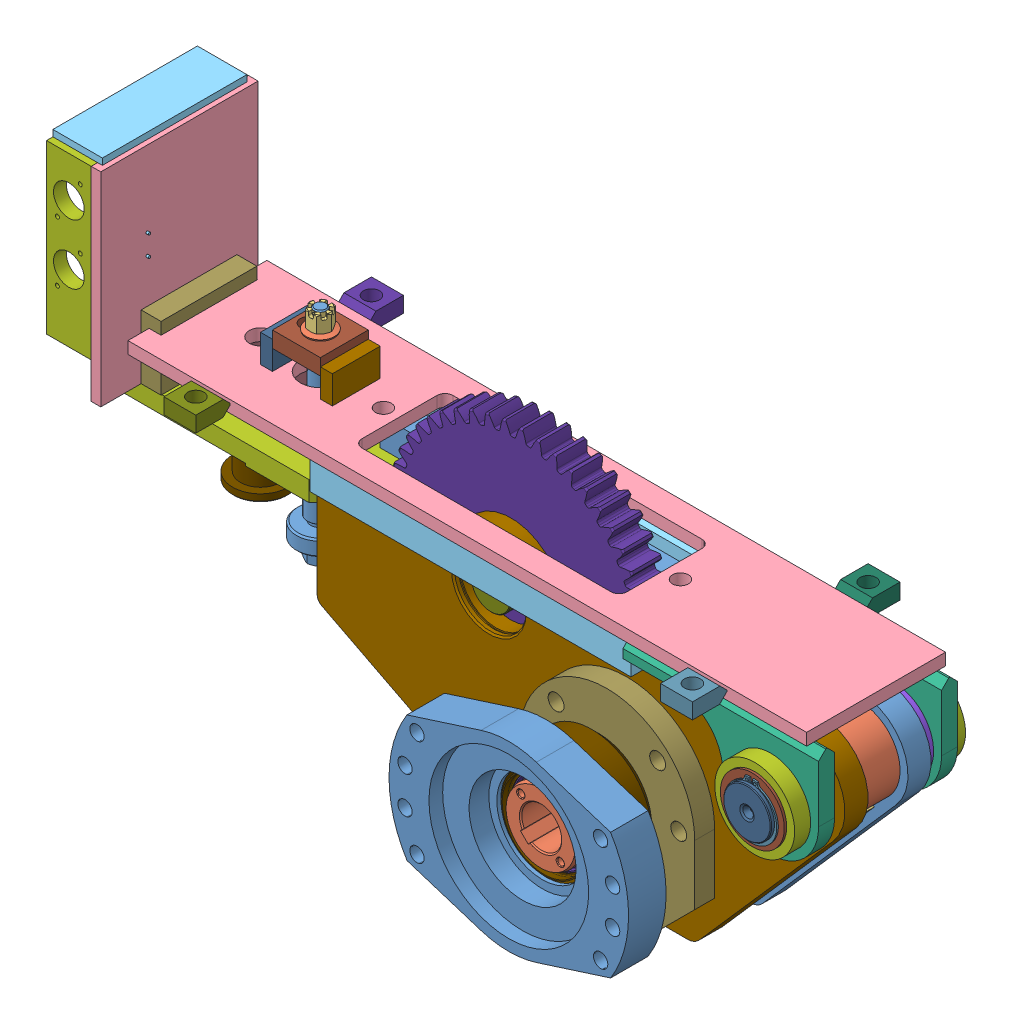
SolidWorks assembly g1_3_1_1, configuration 默认. Lengths in mm.
Overall size (943 530 331.8).
107 component instances, 72 part files, 57 mates.
Components (placement in the parent):
- g1_3_1_1_5_1-1: g1_3_1_1_5_1 [默认] at (328.5367 -95 30) x (-1 0 0) z (0 1 0) size (926 108 318.6)
  - g1_3_1_1_5-1_af1_1-1: g1_3_1_1_5-1_af1_1 [默认] at origin size (661 29 318.6)
  - g1_3_1_1_5-2_af0_1-1: g1_3_1_1_5-2_af0_1 [默认] at (-213.2 29 0) size (100 50 100)
  - g1_3_1_1_5-4_1-1: g1_3_1_1_5-4_1 [默认] at (-149.9151 54 -132.7301) x (0 1 0) z (-0.659692 0 0.751536) size (50 10 223)
  - g1_3_1_1_5-5_1-1: g1_3_1_1_5-5_1 [默认] at (20.5 54 -217) x (1 0 0) z (0 1 0) size (194 10 50)
  - g1_3_1_1_5-6_1-1: g1_3_1_1_5-6_1 [默认] at (248.4498 54 -161.5242) x (0 1 0) z (0.890083 0 0.455798) size (50 10 284)
  - g1_3_1_1_5-7_1-1: g1_3_1_1_5-7_1 [默认] at (377.8 54 -43.9) x (0 0 -1) z (0 1 0) size (87 10 50)
  - g1_3_1_1_5-9_af0_1-1: g1_3_1_1_5-9_af0_1 [默认] at (502.8 54 24.6) x (1 0 0) z (0 1 0) size (300 25 108)
  - g1_3_1_1_5-8_1-1: g1_3_1_1_5-8_1 [默认] at (437.8 54 49.6) x (1 0 0) z (0 1 0) size (60 50 60)
  - g1_3_1_1_5-1_af0_1-1: g1_3_1_1_5-1_af0_1 [默认] at (0 79 0) size (661 29 318.6)
- g1_3_1_1_4_1-1: g1_3_1_1_4_1 [默认] at (541.7367 -95 -33.3) x (1 0 0) z (0 -1 0) size (80 234 80)
  - g1_3_1_1_4-1_1-1: g1_3_1_1_4-1_1 [默认] at origin size (60 234 60.04)
  - g1_3_1_1_4-3_1-2: g1_3_1_1_4-3_1 [默认] at (0 224.3 0) size (80 3 80)
  - g1_3_1_1_4-2_1-1: g1_3_1_1_4-2_1 [默认] at (0 174.3 0) size (72 50 72)
  - g1_3_1_1_4-2_1-2: g1_3_1_1_4-2_1 [默认] at (0 9.7 0) size (72 50 72)
  - g1_3_1_1_4-2_1-3: g1_3_1_1_4-2_1 [默认] at (0 62.7 0) size (72 50 72)
  - g1_3_1_1_4-2_1-4: g1_3_1_1_4-2_1 [默认] at (0 121.3 0) size (72 50 72)
- g1_3_1_1_2_1-1: g1_3_1_1_2_1 [默认] at (328.5367 -195.4 0) x (1 0.000801 0) z (0.000801 -1 0) size (219.6 152 245)
  - g1_3_1_1_2-1_1-1: g1_3_1_1_2-1_1 [默认] at origin size (219.6 61 245)
  - g1_3_1_1_2-2_1-1: g1_3_1_1_2-2_1 [默认] at (0 152 0) x (-0.047609 0 0.998866) z (0 1 0) size (120.16 120.16 117)
  - g1_3_1_1_2-3_1-1: g1_3_1_1_2-3_1 [默认] at (-20.1525 129 20.1525) x (0 -1 0) z (0.707107 0 0.707107) size (28 11 14)
- g1_3_1_1_3_1-1: g1_3_1_1_3_1 [默认] at (155.7367 -78.4 83.75) x (0 0 -1) z (-0.004458 0.99999 0) size (103.5 321.87 322.01)
  - g1_3_1_1_3-1_1-1: g1_3_1_1_3-1_1 [默认] at origin size (103.5 52 52)
  - _X2_60F08F6E_X0_g1_3_1_1_3-2_1-1: _X2_60F08F6E_X0_g1_3_1_1_3-2_1 [默认] at (25 0 0) x (0 0 1) z (1 0 0) size (322.01 321.87 50.08)
- g1_3_1_1_1_2-1: g1_3_1_1_1_2 [默认] at (328.5367 -195.4 123.8) x (1 0.000801 0) z (0.000801 -1 0) size (300 165.8 228)
  - g1_3_1_1_1_1_1-1: g1_3_1_1_1_1_1 [默认] at origin size (300 112 228)
    - g1_3_1_1_1_1-2_af0_1-1: g1_3_1_1_1_1-2_af0_1 [默认] at (0 50 0) size (150 65 150)
    - g1_3_1_1_1_1-3_af0_1-1: g1_3_1_1_1_1-3_af0_1 [默认] at (0 140 0) size (300 47 228)
  - g1_3_1_1_1-2_1-1: g1_3_1_1_1-2_1 [默认] at (0 122.2 0) x (0.707107 0 0.707107) z (0.707107 0 -0.707107) size (90 126 90)
  - 80_gb894_1_1-1: 80_gb894_1_1 [默认] at (-2.4 11.1 -38.1746) x (1 0 0) z (0 -1 0) size (85.83 90.87 2.5)
- g1_3_1_1_6_1-1: g1_3_1_1_6_1 [默认] at (155.7367 0 84) x (-1 0 0) z (0 0 1) size (875 200 260)
  - g1_3_1_1_6-4_af0_1-1: g1_3_1_1_6-4_af0_1 [默认] at origin size (850 15 174)
  - g1_3_1_1_6-8_1-1: g1_3_1_1_6-8_1 [默认] at (0 40 57) x (1 0 0) z (0 -1 0) size (402 20 44.8)
  - g1_3_1_1_6-8_1-2: g1_3_1_1_6-8_1 [默认] at (0 40 -77) x (1 0 0) z (0 -1 0) size (402 20 44.8)
  - g1_3_1_1_6-1_1-1: g1_3_1_1_6-1_1 [默认] at (-386 95 -87) x (1 0 0) z (0 -1 0) size (245 20 140)
  - g1_3_1_1_6-1_1-2: g1_3_1_1_6-1_1 [默认] at (-386 95 67) x (1 0 0) z (0 -1 0) size (245 20 140)
  - g1_3_1_1_6-3_1-1: g1_3_1_1_6-3_1 [默认] at (-386 95 87) x (-1 0 0) z (0 1 0) size (100 20 100)
  - g1_3_1_1_6-3_1-2: g1_3_1_1_6-3_1 [默认] at (-386 95 -107) x (-1 0 0) z (0 1 0) size (100 20 100)
  - g1_3_1_1_6-2_1-1: g1_3_1_1_6-2_1 [默认] at (-386 95 57) x (-1 0 0) z (0 1 0) size (100 10 100)
  - g1_3_1_1_6-2_1-2: g1_3_1_1_6-2_1 [默认] at (-386 95 -57) x (1 0 0) z (0 1 0) size (100 10 100)
  - g1_3_1_1_6-9_1-1: g1_3_1_1_6-9_1 [默认] at (220 -17 0) x (0 1 0) z (0 0 -1) size (35 15 60)
  - g1_3_1_1_6-9_af0_1-1: g1_3_1_1_6-9_af0_1 [默认] at (310 -17 0) x (0 1 0) z (0 0 1) size (35 15 60)
  - g1_3_1_1_6-10_1-1: g1_3_1_1_6-10_1 [默认] at (265 -45 0) size (60 20 60)
  - g1_3_1_1_6-12_af0_1-1: g1_3_1_1_6-12_af0_1 [默认] at (434 25 0.5) x (0 0 1) z (0 -1 0) size (120 25 80)
  - g1_3_1_1_6-11_af0_1-1: g1_3_1_1_6-11_af0_1 [默认] at (357 15 0) size (94 40 60)
  - g1_3_1_1_6-5_af0_1-1: g1_3_1_1_6-5_af0_1 [默认] at (-311 -5 108.5) x (0 0 -1) z (1 0 0) size (43 19.6 40)
  - g1_3_1_1_6-5_af1_1-1: g1_3_1_1_6-5_af1_1 [默认] at (-311 -5 -108.5) x (0 0 1) z (-1 0 0) size (43 19.6 40)
  - g1_3_1_1_6-5_af2_1-1: g1_3_1_1_6-5_af2_1 [默认] at (311 -5 108.5) x (0 0 -1) z (1 0 0) size (43 19.6 40)
  - g1_3_1_1_6-5_af3_1-1: g1_3_1_1_6-5_af3_1 [默认] at (311 -5 -108.5) x (0 0 1) z (-1 0 0) size (43 19.6 40)
- g1_3_1_1-1_1-1: g1_3_1_1-1_1 [默认] at (-184.2633 -45.5 84) x (1 0 -0.00083) z (-0.00083 0 -1) size (70 135 70)
- g1_3_1_1_7_1-1: g1_3_1_1_7_1 [默认] at (-109.2633 -16.0167 84) x (0 1 0) z (0.020278 0 0.999794) size (272.02 60 60)
  - g1_3_1_1_7-1_1-1: g1_3_1_1_7-1_1 [默认] at origin size (272.02 60 60)
  - a35_5_gb1972_1-1: a35_5_gb1972_1 [默认] at (39.2167 0 0) x (0 0.075145 0.997173) z (0 0.997173 -0.075145) size (35.5 7.2 35.5)
  - a35_5_gb1972_1-2: a35_5_gb1972_1 [默认] at (62.8167 0 0) x (0 -0.99777 0.066751) z (0 -0.066751 -0.99777) size (35.5 7.2 35.5)
  - m16a_gb6178_1-1: m16a_gb6178_1 [默认] at (85.8167 13.8564 0) x (0 -1 0) z (-1 0 0) size (27.71 24 20.8)
- g1_3_1_1_8_1-1: g1_3_1_1_8_1 [默认] at (-273.2633 62.5 96.5) x (0 0 -1) z (0 1 0) size (197 71 268.3)
  - g1_3_1_1_8_1_af0_1-1: g1_3_1_1_8_1_af0_1 [默认] at origin size (197 68 263)
    - g1_3_1_1_8_1-3_af1_1-1: g1_3_1_1_8_1-3_af1_1 [默认] at origin size (197 12 255)
    - g1_3_1_1_8_1-1_1-1: g1_3_1_1_8_1-1_1 [默认] at (0 37 127.5) x (1 0 0) z (0 -1 0) size (181 8 62)
    - g1_3_1_1_8_1-2_af1_1-1: g1_3_1_1_8_1-2_af1_1 [默认] at (98.5 40 22.5) x (0 1 0) z (0 0 1) size (56 16 210)
    - g1_3_1_1_8_1-2_af0_1-1: g1_3_1_1_8_1-2_af0_1 [默认] at (-98.5 40 22.5) x (0 1 0) z (0 0 -1) size (56 16 210)
    - g1_3_1_1_8_1-5_1-1: g1_3_1_1_8_1-5_1 [默认] at (0 40 -82.5) x (1 0 0) z (0 1 0) size (165 8 56)
    - g1_3_1_1_8_1-6_1-1: g1_3_1_1_8_1-6_1 [默认] at (27.5 40 -106) x (0 1 0) z (0 0 -1) size (56 6 31)
    - g1_3_1_1_8_1-6_1-2: g1_3_1_1_8_1-6_1 [默认] at (-8.5 40 -106) x (0 1 0) z (0 0 -1) size (56 6 31)
    - g1_3_1_1_8_1-4_af1_1-1: g1_3_1_1_8_1-4_af1_1 [默认] at (-10 12 5) size (105 17 85)
    - g1_3_1_1_8_1-8_af0_1-1: g1_3_1_1_8_1-8_af0_1 [默认] at (12.5 40 -127.5) x (0 1 0) z (1 0 0) size (56 6 54)
  - g1_3_1_1_8-3_1-1: g1_3_1_1_8-3_1 [默认] at (12.5 37 -32.7987) x (0 0 -1) z (0 1 0) size (229 15 15)
  - g1_3_1_1_8-6_1-1: g1_3_1_1_8-6_1 [默认] at (12.5 37 30.1) x (-1 0 0) z (0 1 0) size (26 60 26)
  - g1_3_1_1_8-5_1-1: g1_3_1_1_8-5_1 [默认] at (12.5 29 -27.5) size (60 24 20)
  - g1_3_1_1_8-9_af0_1-1: g1_3_1_1_8-9_af0_1 [默认] at (-42.5 17 5.5) size (34 10 74)
  - g1_3_1_1_8-10_1-1: g1_3_1_1_8-10_1 [默认] at (12.5 37 -127.5) x (1 0 0) z (0 1 0) size (40 2 32)
  - ya2x20x90-2_gb2089_af0_1-1: ya2x20x90-2_gb2089_af0_1 [默认] at (12.5 37 -82.5) x (0 0 -1) z (1 0 0) size (92.3 24.62 24.71)
  - 14x2_65_gb3452_1_1-1: 14x2_65_gb3452_1_1 [默认] at (12.5 37 -124.5) x (0 0 1) z (0 1 0) size (2.65 19.38 19.38)
  - 15_gb894_1_1-1: 15_gb894_1_1 [默认] at (12 29.8675 -73.9) size (17.18 18.67 1.11)
  - 15_gb894_1_1-2: 15_gb894_1_1 [默认] at (12 29.8675 29) size (17.18 18.67 1.11)
  - 8_gb93_1-1: 8_gb93_1 [默认] at (32.5 53 -27.5) x (-1 0 0) z (0 1 0) size (12.3 12.3 2.1)
  - m8x40_gb5782_1-1: m8x40_gb5782_1 [默认] at (32.5 55.1 -27.5) size (15.01 45.3 13)
  - 8_gb93_1-2: 8_gb93_1 [默认] at (-7.5 53 -27.5) x (-1 0 0) z (0 1 0) size (12.3 12.3 2.1)
  - m8x40_gb5782_1-2: m8x40_gb5782_1 [默认] at (-7.5 55.1 -27.5) size (15.01 45.3 13)
  - m3x10_gb818_1-1: m3x10_gb818_1 [默认] at (57.5 2 60.5) size (5.81 12.5 5.77)
  - m3x10_gb818_1-2: m3x10_gb818_1 [默认] at (57.5 2 100.5) size (5.81 12.5 5.77)
  - m3x10_gb818_1-3: m3x10_gb818_1 [默认] at (-17.5 2 100.5) size (5.81 12.5 5.77)
  - m3x10_gb818_1-4: m3x10_gb818_1 [默认] at (-57.5 2 100.5) size (5.81 12.5 5.77)
  - m3x30_gb818_1-1: m3x30_gb818_1 [默认] at (-40.5 -3 7.5) size (5.81 32.5 5.77)
  - m3x30_gb818_1-2: m3x30_gb818_1 [默认] at (-40.5 -3 32.9) size (5.81 32.5 5.77)
  - 6_gb93_1-9: 6_gb93_1 [默认] at (-52.5 28.6 -17.5) x (1 0 0) z (0 -1 0) size (9.3 9.3 1.6)
  - m6x20_gb5783_1-9: m6x20_gb5783_1 [默认] at (-52.5 28.6 -17.5) size (11.55 24 10)
  - 6_gb93_1-10: 6_gb93_1 [默认] at (-32.5 28.6 -17.5) x (1 0 0) z (0 -1 0) size (9.3 9.3 1.6)
  - m6x20_gb5783_1-10: m6x20_gb5783_1 [默认] at (-32.5 28.6 -17.5) size (11.55 24 10)
  - 5x14_gb119_2_1-1: 5x14_gb119_2_1 [默认] at (-42.5 27 -3.5) size (5 14 5)
  - m3x6_gb818_1-1: m3x6_gb818_1 [默认] at (27.5 37 -123.5) x (1 0 0) z (0 1 0) size (5.81 8.5 5.77)
  - m3x6_gb818_1-2: m3x6_gb818_1 [默认] at (-2.5 37 -123.5) x (1 0 0) z (0 1 0) size (5.81 8.5 5.77)
- _X2_57AB5708_X0_16_gb93_1-9: _X2_57AB5708_X0_16_gb93_1 [默认] at (-285.2633 -50 44) x (0 0.924225 0.381849) z (-1 0 0) size (24.4 24.4 4.1)
- _X2_87BA6813_X0_m16x35_gb5783_10_1-1: _X2_87BA6813_X0_m16x35_gb5783_10_1 [默认] at (-289.3633 -50 44) x (0 -0.866025 -0.5) z (0 0.5 -0.866025) size (27.71 45 24)
- _X2_57AB5708_X0_16_gb93_1-10: _X2_57AB5708_X0_16_gb93_1 [默认] at (-285.2633 -50 124) x (0 0.924225 0.381849) z (-1 0 0) size (24.4 24.4 4.1)
- _X2_87BA6813_X0_m16x35_gb5783_10_1-2: _X2_87BA6813_X0_m16x35_gb5783_10_1 [默认] at (-289.3633 -50 124) x (0 -0.866025 -0.5) z (0 0.5 -0.866025) size (27.71 45 24)
- g1_3_1_1_1_1-1_af0_1-1: g1_3_1_1_1_1-1_af0_1 [默认] at (328.5367 -195.4 113) x (1 0 0) z (0 -1 0) size (220 42 245)
- g1_3_1_1_7-2_1-1: g1_3_1_1_7-2_1 [默认] at (-141.0175 -95.4 83.9778) x (1 0 0.0007) z (0 -1 0) size (63.51 55 25)
- g1_3_1_1_4-3_1-2: g1_3_1_1_4-3_1 [默认] at (541.7367 -95 -23.6) x (-0.923728 -0.383049 0) z (0.383049 -0.923728 0) size (80 3 80)
- 60_gb894_1_1-2: 60_gb894_1_1 [默认] at (543.6867 -66.5668 -28.6) x (-1 0 0) z (0 0 1) size (65.16 69.76 2)
- 60_gb894_1_1-3: 60_gb894_1_1 [默认] at (543.6867 -66.5668 194) x (-1 0 0) z (0 0 1) size (65.16 69.76 2)
- 16x10x45_gb1096_1-2: 16x10x45_gb1096_1 [默认] at (155.6253 -53.4002 83.25) x (0 0 -1) z (0.004458 -0.99999 0) size (45 16 10)
- g1_3_1_1_1-1_1-1: g1_3_1_1_1-1_1 [默认] at (328.5367 -195.4 210.3) x (0 0 -1) z (0.990882 0.134732 0) size (20 110 110)
- b90x110x12_gb9877_1_rubber_1-1: b90x110x12_gb9877_1_rubber_1 [默认] at (328.5367 -195.4 194.3) x (1 0 0) z (0 -1 0) size (108.6 12 108.6)
- b90x110x12_gb9877_1_rubber_1-2: b90x110x12_gb9877_1_rubber_1 [默认] at (328.5367 -195.4 226.3) x (1 0 0) z (0 1 0) size (108.6 12 108.6)
- b90x110x12_gb9877_1_frame_1-1: b90x110x12_gb9877_1_frame_1 [默认] at (328.5367 -195.4 232.3) x (-0.923728 -0.383049 0) z (-0.383049 0.923728 0) size (107.2 9.5 107.2)
- b90x110x12_gb9877_1_frame_1-2: b90x110x12_gb9877_1_frame_1 [默认] at (328.5367 -195.4 188.3) x (0.999991 -0.004354 0) z (0.004354 0.999991 0) size (107.2 9.5 107.2)
Mates (geometry in assembly coordinates):
- 重合1: coincident anti-aligned: plane of g1_3_1_1_2_1-1/g1_3_1_1_2-3_1-1 through (303.4466 -210.6229 129) normal (-0.707673 0.70654 0); plane of g1_3_1_1_1_2-1/g1_3_1_1_1-2_1-1 through (303.2347 -210.8352 246) normal (0.707673 -0.70654 0)
- 重合2: coincident anti-aligned: plane of g1_3_1_1_2_1-1/g1_3_1_1_2-2_1-1 through (328.5367 -195.4 120) normal (0 0 1); plane of g1_3_1_1_1_2-1/g1_3_1_1_1-2_1-1 through (328.5367 -195.4 120) normal (0 0 -1)
- 同心3: concentric aligned: cylinder of g1_3_1_1_2_1-1/g1_3_1_1_2-2_1-1 through (328.5367 -195.4 29.15) axis (0 0 1) radius 25; cylinder of g1_3_1_1_1_2-1/g1_3_1_1_1-2_1-1 through (328.5367 -195.4 246) axis (0 0 1) radius 25
- 同心9: concentric anti-aligned: cylinder of g1_3_1_1_8_1-1/g1_3_1_1_8_1_af0_1-1/g1_3_1_1_8_1-3_af1_1-1 through (-285.2633 -50 124) axis (1 0 0) radius 8.5; cylinder of _X2_87BA6813_X0_m16x35_gb5783_10_1-2 through (-252.6133 -50 124) axis (-1 0 0) radius 8
- 同心12: concentric anti-aligned: cylinder of g1_3_1_1_6_1-1/g1_3_1_1_6-12_af0_1-1 through (-229.747 -50 44) axis (1 0 0) radius 7; cylinder of _X2_87BA6813_X0_m16x35_gb5783_10_1-1 through (-252.6133 -50 44) axis (-1 0 0) radius 8
- 同心13: concentric aligned: cylinder of _X2_57AB5708_X0_16_gb93_1-10 through (-285.2633 -50 124) axis (-1 0 0) radius 8.1; cylinder of _X2_87BA6813_X0_m16x35_gb5783_10_1-2 through (-252.6133 -50 124) axis (-1 0 0) radius 8
- 同心14: concentric aligned: cylinder of _X2_57AB5708_X0_16_gb93_1-9 through (-285.2633 -50 44) axis (-1 0 0) radius 8.1; cylinder of _X2_87BA6813_X0_m16x35_gb5783_10_1-1 through (-252.6133 -50 44) axis (-1 0 0) radius 8
- 重合3: coincident anti-aligned: plane of _X2_57AB5708_X0_16_gb93_1-9 through (-289.3633 -50 44) normal (-1 0 0); plane of _X2_87BA6813_X0_m16x35_gb5783_10_1-1 through (-289.3633 -50 44) normal (1 0 0)
- 重合4: coincident anti-aligned: plane of _X2_57AB5708_X0_16_gb93_1-10 through (-289.3633 -50 124) normal (-1 0 0); plane of _X2_87BA6813_X0_m16x35_gb5783_10_1-2 through (-289.3633 -50 124) normal (1 0 0)
- 同心15: concentric aligned: cylinder of g1_3_1_1_8_1-1/g1_3_1_1_8_1_af0_1-1/g1_3_1_1_8_1-3_af1_1-1 through (-285.2633 -50 44) axis (-1 0 0) radius 8.5; cylinder of _X2_87BA6813_X0_m16x35_gb5783_10_1-1 through (-252.6133 -50 44) axis (-1 0 0) radius 8
- 同心18: concentric aligned: cylinder of g1_3_1_1_6_1-1/g1_3_1_1_6-11_af0_1-1 through (-184.2633 71.0063 84) axis (0 -1 0) radius 14; cylinder of g1_3_1_1-1_1-1 through (-184.2633 -19.25 84) axis (0 -1 0) radius 15
- 同心20: concentric anti-aligned: cylinder of g1_3_1_1_5_1-1/g1_3_1_1_5-9_af0_1-1 through (-184.2633 -95.4 84) axis (0 1 0) radius 27; cylinder of g1_3_1_1-1_1-1 through (-184.2633 -50.5 84) axis (0 -1 0) radius 25
- 重合10: coincident anti-aligned: plane of g1_3_1_1_8_1-1/g1_3_1_1_8_1_af0_1-1/g1_3_1_1_8_1-3_af1_1-1 through (-285.2633 62.5 96.5) normal (-1 0 0); plane of _X2_57AB5708_X0_16_gb93_1-9 through (-285.2633 -50 44) normal (1 0 0)
- 重合12: coincident anti-aligned: plane of g1_3_1_1_8_1-1/g1_3_1_1_8_1_af0_1-1/g1_3_1_1_8_1-3_af1_1-1 through (-285.2633 62.5 96.5) normal (-1 0 0); plane of _X2_57AB5708_X0_16_gb93_1-10 through (-285.2633 -50 124) normal (1 0 0)
- 重合13: coincident anti-aligned: plane of g1_3_1_1_6_1-1/g1_3_1_1_6-12_af0_1-1 through (-273.2633 0 84) normal (-1 0 0); plane of g1_3_1_1_8_1-1/g1_3_1_1_8_1_af0_1-1/g1_3_1_1_8_1-3_af1_1-1 through (-273.2633 62.5 96.5) normal (1 0 0)
- 同心23: concentric aligned: cylinder of g1_3_1_1_5_1-1/g1_3_1_1_5-1_af1_1-1 through (541.7367 -95 30) axis (0 0 1) radius 36; cylinder of g1_3_1_1_6_1-1/g1_3_1_1_6-3_1-2 through (541.7367 -95 -23) axis (0 0 1) radius 36
- 同心24: concentric aligned: cylinder of g1_3_1_1_4_1-1/g1_3_1_1_4-2_1-2 through (541.7367 -95 -23.6) axis (0 0 1) radius 36; cylinder of g1_3_1_1_6_1-1/g1_3_1_1_6-3_1-2 through (541.7367 -95 -23) axis (0 0 1) radius 36
- 重合14: coincident anti-aligned: plane of g1_3_1_1_4_1-1/g1_3_1_1_4-3_1-2 through (541.7367 -95 191) normal (0 0 -1); plane of g1_3_1_1_6_1-1/g1_3_1_1_6-3_1-1 through (541.7367 -95 191) normal (0 0 1)
- 同心25: concentric aligned: cylinder of g1_3_1_1_5_1-1/g1_3_1_1_5-1_af1_1-1 through (155.7367 -78.4 30) axis (0 0 1) radius 45; cylinder of g1_3_1_1_3_1-1/g1_3_1_1_3-1_1-1 through (155.7367 -78.4 26.825) axis (0 0 1) radius 25
- 同心26: concentric aligned: cylinder of g1_3_1_1_5_1-1/g1_3_1_1_5-1_af1_1-1 through (328.5367 -195.4 30) axis (0 0 1) radius 75; cylinder of g1_3_1_1_2_1-1/g1_3_1_1_2-1_1-1 through (328.5367 -195.4 30) axis (0 0 1) radius 75
- 重合16: coincident anti-aligned: plane of g1_3_1_1_5_1-1/g1_3_1_1_5-1_af1_1-1 through (328.5367 -95 30) normal (0 0 -1); plane of g1_3_1_1_2_1-1/g1_3_1_1_2-1_1-1 through (328.5367 -195.4 30) normal (0 0 1)
- 重合17: coincident anti-aligned: plane of g1_3_1_1_5_1-1/g1_3_1_1_5-1_af1_1-1; plane of ? through (523.5275 -270.9624 278.2595) normal (0 -1 0)
- 重合19: coincident aligned: plane of g1_3_1_1_5_1-1/g1_3_1_1_5-1_af0_1-1 through (155.7367 -78.4 128.8) normal (0 0 1); plane of g1_3_1_1_3_1-1/g1_3_1_1_3-1_1-1 through (155.7367 -78.4 128.8) normal (0 0 1)
- 重合28: coincident anti-aligned: plane of g1_3_1_1_2_1-1/g1_3_1_1_2-1_1-1 through (328.5367 -195.4 0) normal (0 0 -1); plane of assembly through (0 0 0) normal (0 0 1)
- 重合31: coincident aligned: plane of g1_3_1_1_6_1-1/g1_3_1_1_6-4_af0_1-1 through (155.7367 0 84) normal (0 1 0); plane of assembly through (0 0 0) normal (0 1 0)
- 同心28: concentric aligned: cylinder of g1_3_1_1_6_1-1/g1_3_1_1_6-12_af0_1-1 through (-229.747 -50 124) axis (-1 0 0) radius 7; cylinder of _X2_87BA6813_X0_m16x35_gb5783_10_1-2 through (-252.6133 -50 124) axis (-1 0 0) radius 8
- 同心29: concentric aligned: cylinder of g1_3_1_1_5_1-1/g1_3_1_1_5-1_af0_1-1 through (328.5367 -195.4 109) axis (0 0 1) radius 75; cylinder of g1_3_1_1_1_1-1_af0_1-1 through (328.5367 -195.4 -384.4109) axis (0 0 1) radius 75
- 同心30: concentric aligned: cylinder of g1_3_1_1_5_1-1/g1_3_1_1_5-1_af0_1-1 through (264.9367 -131.8 108.5324) axis (0 0 1) radius 5.1; cylinder of g1_3_1_1_1_1-1_af0_1-1 through (264.9367 -131.8 163) axis (0 0 1) radius 10
- 重合33: coincident anti-aligned: plane of g1_3_1_1_5_1-1/g1_3_1_1_5-1_af0_1-1 through (328.5367 -95 138) normal (0 0 1); plane of g1_3_1_1_1_1-1_af0_1-1 through (328.5367 -195.4 138) normal (0 0 -1)
- 平行2: parallel aligned: plane of ? through (593.4401 -66.5668 194.2) normal (1 0 0); plane of g1_3_1_1_6_1-1/g1_3_1_1_6-1_1-2 through (595.2275 -95 151) normal (1 0 0)
- 重合37: coincident anti-aligned: plane of g1_3_1_1_6_1-1/g1_3_1_1_6-11_af0_1-1 through (-154.2633 -50.5 114) normal (0 -1 0); plane of g1_3_1_1-1_1-1 through (-184.2633 -50.5 84) normal (0 1 0)
- 平行5: parallel anti-aligned: plane of g1_3_1_1_8_1-1/g1_3_1_1_8_1_af0_1-1/g1_3_1_1_8_1-5_1-1 through (-313.2633 -28 96.5) normal (0 -1 0); plane of _X2_87BA6813_X0_m16x35_gb5783_10_1-2 through (-289.3633 -38 130.9282) normal (0 1 0)
- 平行6: parallel anti-aligned: plane of g1_3_1_1_8_1-1/g1_3_1_1_8_1_af0_1-1/g1_3_1_1_8_1-5_1-1 through (-313.2633 -28 96.5) normal (0 -1 0); plane of _X2_87BA6813_X0_m16x35_gb5783_10_1-1 through (-289.3633 -38 50.9282) normal (0 1 0)
- 同心33: concentric anti-aligned: cylinder of g1_3_1_1_6_1-1/g1_3_1_1_6-10_1-1 through (-109.2633 45 84) axis (0 -1 0) radius 10; cylinder of g1_3_1_1_7_1-1/g1_3_1_1_7-1_1-1 through (-109.2633 -471.3188 84) axis (0 1 0) radius 8.9
- 同心34: concentric anti-aligned: cylinder of g1_3_1_1_7_1-1/g1_3_1_1_7-1_1-1 through (-109.2633 -471.3188 84) axis (0 1 0) radius 16; cylinder of g1_3_1_1_7-2_1-1 through (-109.2633 -95.4 84) axis (0 -1 0) radius 16.376
- 重合38: coincident anti-aligned: plane of g1_3_1_1_5_1-1/g1_3_1_1_5-8_1-1 through (-109.2633 -95.4 84) normal (0 -1 0); plane of g1_3_1_1_7-2_1-1 through (-141.0175 -95.4 83.9778) normal (0 1 0)
- 距离1: distance = 4 mm anti-aligned: plane of g1_3_1_1_7_1-1/g1_3_1_1_7-1_1-1 through (-109.2633 21 84) normal (0 1 0); plane of g1_3_1_1_6_1-1/g1_3_1_1_6-10_1-1 through (-109.2633 25 84) normal (0 -1 0)
- 重合40: coincident anti-aligned: plane of g1_3_1_1_4_1-1/g1_3_1_1_4-2_1-2 through (541.7367 -95 -23.6) normal (0 0 -1); plane of g1_3_1_1_4-3_1-2 through (541.7367 -95 -23.6) normal (0 0 1)
- 同心35: concentric anti-aligned: cylinder of g1_3_1_1_4_1-1/g1_3_1_1_4-1_1-1 through (541.7367 -95 -33.3) axis (0 0 1) radius 30; cylinder of g1_3_1_1_4-3_1-2 through (541.7367 -95 -23.6) axis (0 0 -1) radius 30.5
- 同心36: concentric aligned: cylinder of g1_3_1_1_4_1-1/g1_3_1_1_4-1_1-1 through (541.7367 -95 450.0941) axis (0 0 1) radius 28.5; cylinder of 60_gb894_1_1-2 through (541.7367 -95 -28.6) axis (0 0 1) radius 28.5
- 重合41: coincident anti-aligned: plane of g1_3_1_1_4-3_1-2 through (541.7367 -95 -26.6) normal (0 0 -1); plane of 60_gb894_1_1-2 through (543.6867 -66.5668 -26.6) normal (0 0 1)
- 重合42: coincident anti-aligned: plane of g1_3_1_1_4_1-1/g1_3_1_1_4-3_1-2 through (541.7367 -95 194) normal (0 0 1); plane of 60_gb894_1_1-3 through (543.6867 -66.5668 194) normal (0 0 -1)
- 同心37: concentric aligned: cylinder of g1_3_1_1_4_1-1/g1_3_1_1_4-1_1-1 through (541.7367 -95 -282.6941) axis (0 0 1) radius 28.5; cylinder of 60_gb894_1_1-3 through (541.7367 -95 194) axis (0 0 1) radius 28.5
- 重合51: coincident anti-aligned: plane of g1_3_1_1_3_1-1/g1_3_1_1_3-1_1-1 through (155.6476 -58.4002 83.75) normal (-0.004458 0.99999 0); plane of 16x10x45_gb1096_1-2 through (155.6476 -58.4002 83.25) normal (0.004458 -0.99999 0)
- 同心39: concentric aligned: cylinder of g1_3_1_1_3_1-1/g1_3_1_1_3-1_1-1 through (155.6208 -52.4003 68.75) axis (-0.004458 0.99999 0) radius 8; cylinder of 16x10x45_gb1096_1-2 through (155.6476 -58.4158 68.75) axis (-0.004458 0.99999 0) radius 8
- 重合52: coincident anti-aligned: plane of g1_3_1_1_3_1-1/g1_3_1_1_3-1_1-1 through (163.6207 -52.3646 98.75) normal (-0.99999 -0.004458 0); plane of 16x10x45_gb1096_1-2 through (163.6029 -48.3646 60.75) normal (0.99999 0.004458 0)
- 重合53: coincident: plane of ? through (335.0708 -180.6788 216.0533) normal (0 0 1); plane of g1_3_1_1_1-1_1-1 through (322.0275 -195.4 213.1) normal (0 0 1)
- 同心40: concentric anti-aligned: cylinder of g1_3_1_1_1_2-1/g1_3_1_1_1-2_1-1 through (328.5367 -195.4 246) axis (0 0 -1) radius 45; cylinder of g1_3_1_1_1-1_1-1 through (328.5367 -195.4 334.6188) axis (0 0 1) radius 49
- 同心44: concentric anti-aligned: cylinder of g1_3_1_1_1-1_1-1 through (328.5367 -195.4 334.6188) axis (0 0 1) radius 53; cylinder of b90x110x12_gb9877_1_rubber_1-2 through (328.5367 -195.4 368.2188) axis (0 0 -1) radius 54.2995
- 重合59: coincident anti-aligned: plane of g1_3_1_1_1-1_1-1 through (328.5367 -195.4 355.6188) normal (0 0 1); plane of b90x110x12_gb9877_1_rubber_1-2 through (328.5367 -195.4 355.6188) normal (0 0 -1)
- 重合60: coincident anti-aligned: plane of b90x110x12_gb9877_1_rubber_1-2 through (328.5367 -195.4 367.6188) normal (0 0 1); plane of b90x110x12_gb9877_1_frame_1-1 through (328.5367 -195.4 367.6188) normal (0 0 -1)
- 重合61: coincident anti-aligned: plane of g1_3_1_1_1-1_1-1 through (328.5367 -195.4 335.6188) normal (0 0 -1); plane of b90x110x12_gb9877_1_rubber_1-1 through (328.5367 -195.4 335.6188) normal (0 0 1)
- 同心45: concentric aligned: cylinder of g1_3_1_1_1-1_1-1 through (328.5367 -195.4 334.6188) axis (0 0 1) radius 53; cylinder of b90x110x12_gb9877_1_rubber_1-1 through (328.5367 -195.4 323.0188) axis (0 0 1) radius 54.2995
- 重合62: coincident anti-aligned: plane of b90x110x12_gb9877_1_rubber_1-1 through (328.5367 -195.4 323.6188) normal (0 0 -1); plane of b90x110x12_gb9877_1_frame_1-2 through (328.5367 -195.4 323.6188) normal (0 0 1)
- 同心46: concentric anti-aligned: cylinder of b90x110x12_gb9877_1_rubber_1-1 through (328.5367 -195.4 323.0188) axis (0 0 1) radius 54.2995; cylinder of b90x110x12_gb9877_1_frame_1-2 through (328.5367 -195.4 324.0938) axis (0 0 -1) radius 52.3
- 同心47: concentric anti-aligned: cylinder of g1_3_1_1_1-1_1-1 through (328.5367 -195.4 334.6188) axis (0 0 1) radius 49; circle of b90x110x12_gb9877_1_frame_1-1
- 重合63: coincident anti-aligned: plane of g1_3_1_1_1_2-1/g1_3_1_1_1_1_1-1/g1_3_1_1_1_1-2_af0_1-1 through (328.5367 -195.4 178.8) normal (0 0 1); plane of b90x110x12_gb9877_1_frame_1-2 through (328.5367 -195.4 178.8) normal (0 0 -1)
